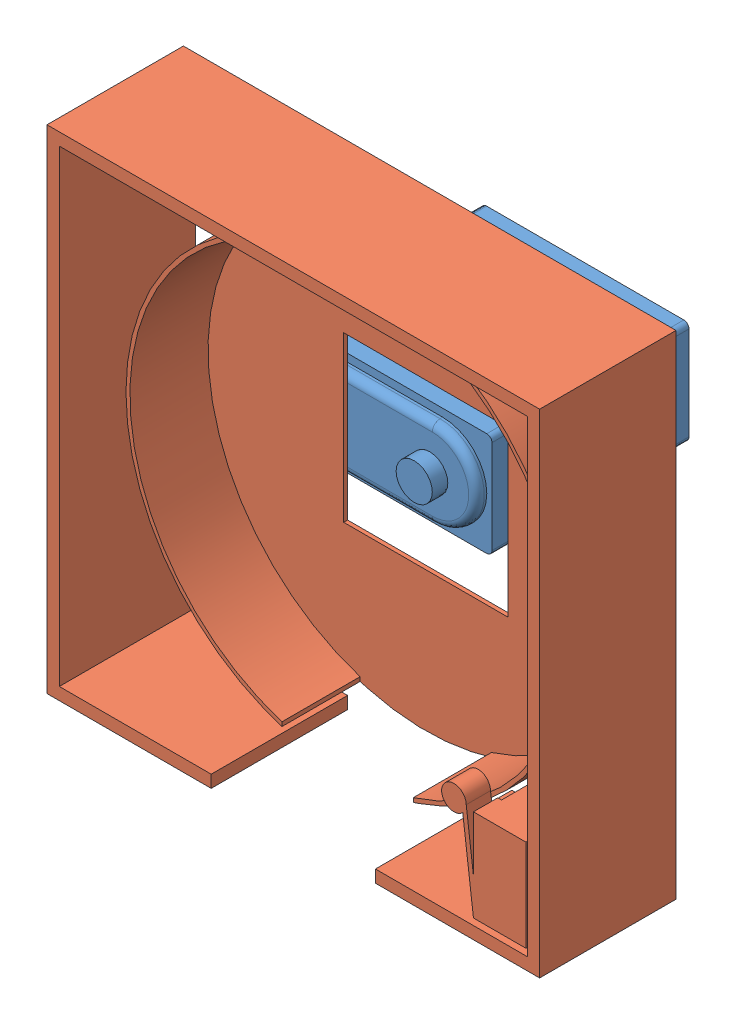
SolidWorks assembly FruitDispenseAssm, configuration Default. Lengths in mm.
Overall size (95.25 95.25 66.48).
2 component instances, 2 part files, 5 mates.
Components (placement in the parent):
- servo-1: servo [Default] at (-10.033 0 -40.1) size (52.83 20.07 43.1)
- FruitDispenseDrum-1: FruitDispenseDrum [Default] x (-1 0 0) z (0 0 -1) size (95.25 95.25 26.38)
Mates (geometry in assembly coordinates):
- Coincident1: coincident anti-aligned: plane of FruitDispenseDrum-1 through (0 0 0) normal (0 0 -1); plane of assembly through (0 0 0) normal (0 0 1)
- Coincident2: coincident aligned: plane of FruitDispenseDrum-1; plane of assembly through (0 0 0) normal (0 1 0)
- Coincident3: coincident anti-aligned: plane of FruitDispenseDrum-1 through (0 0 0) normal (-1 0 0); plane of assembly through (0 0 0) normal (1 0 0)
- Concentric1: concentric aligned: cylinder of servo-1 through (0 0 3) axis (0 0 -1) radius 3.5; line of assembly
- Coincident4: coincident anti-aligned: plane of servo-1 through (0.5 0 0) normal (0 0 1); plane of FruitDispenseDrum-1 through (0 0 0) normal (0 0 -1)
